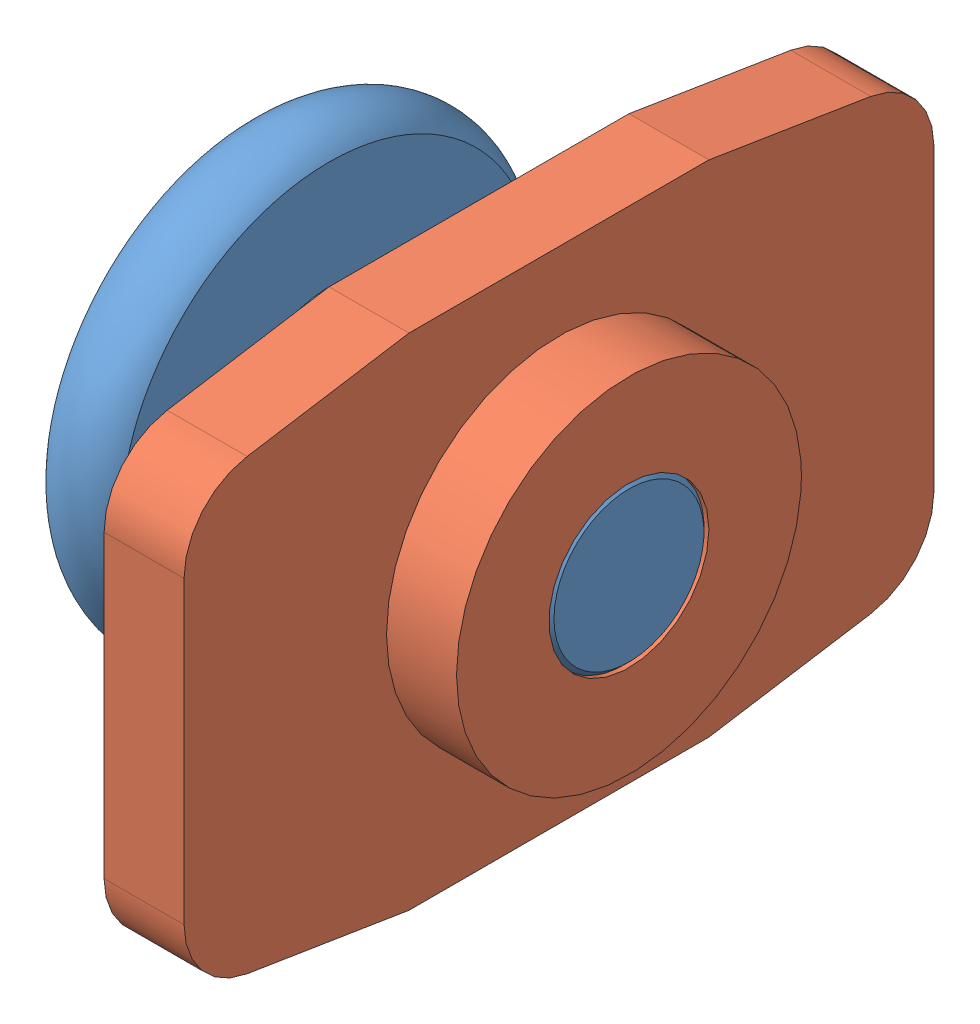
SolidWorks assembly M4_Low_Profile_Screw_with_T_nut, configuration M4-8mm. Lengths in mm.
Overall size (9.62 10 15).
2 component instances, 2 part files, 2 mates.
Components (placement in the parent):
- Low Profile Screw M4-1: Low Profile Screw M4 [M5 x 8] at (4.1063 1.1517 0.1173) size (9.62 9 9)
- Tee Nut M4-1: Tee Nut M4 [Default] at (1.1063 1.1517 0.1173) x (0 0 -1) z (1 0 0)
Mates (geometry in assembly coordinates):
- Concentric1: concentric aligned: circle of Low Profile Screw M4-1; circle of Tee Nut M4-1
- Coincident1: coincident aligned: plane of Low Profile Screw M4-1 through (4.1063 1.1517 0.1173) normal (1 0 0); plane of Tee Nut M4-1 through (4.1063 1.1517 0.1173) normal (1 0 0)
